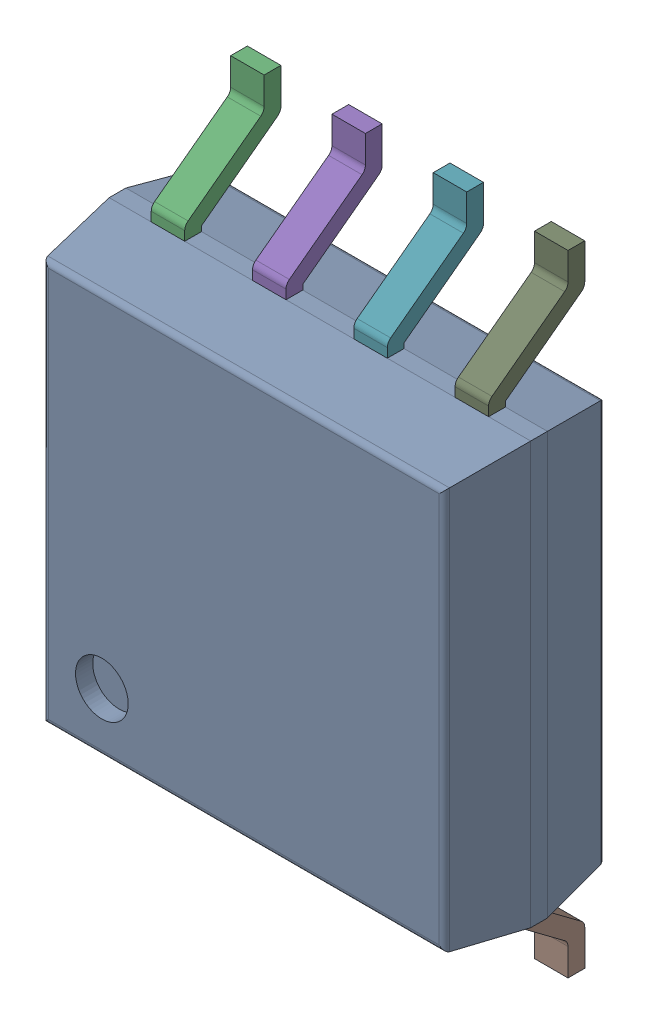
SolidWorks assembly IC6_1.step, configuration Default. Lengths in mm.
Overall size (5.29 7.9 2.16).
3 component instances, 2 part files, 0 mates.
Components (placement in the parent):
- 6348792448_1.step-3: 6348792448_1.step [Default] at (368.3196 283.055 0) x (0 1 0) z (0 0 1) size (7.9 5.29 2.16)
  - Body-12_1.step-5: Body-12_1.step [Default] at origin size (5.29 5.29 2.01)
  - PinsArrayLR-13_1.step-5: PinsArrayLR-13_1.step [Default] at origin size (7.9 4.23 1.21)
